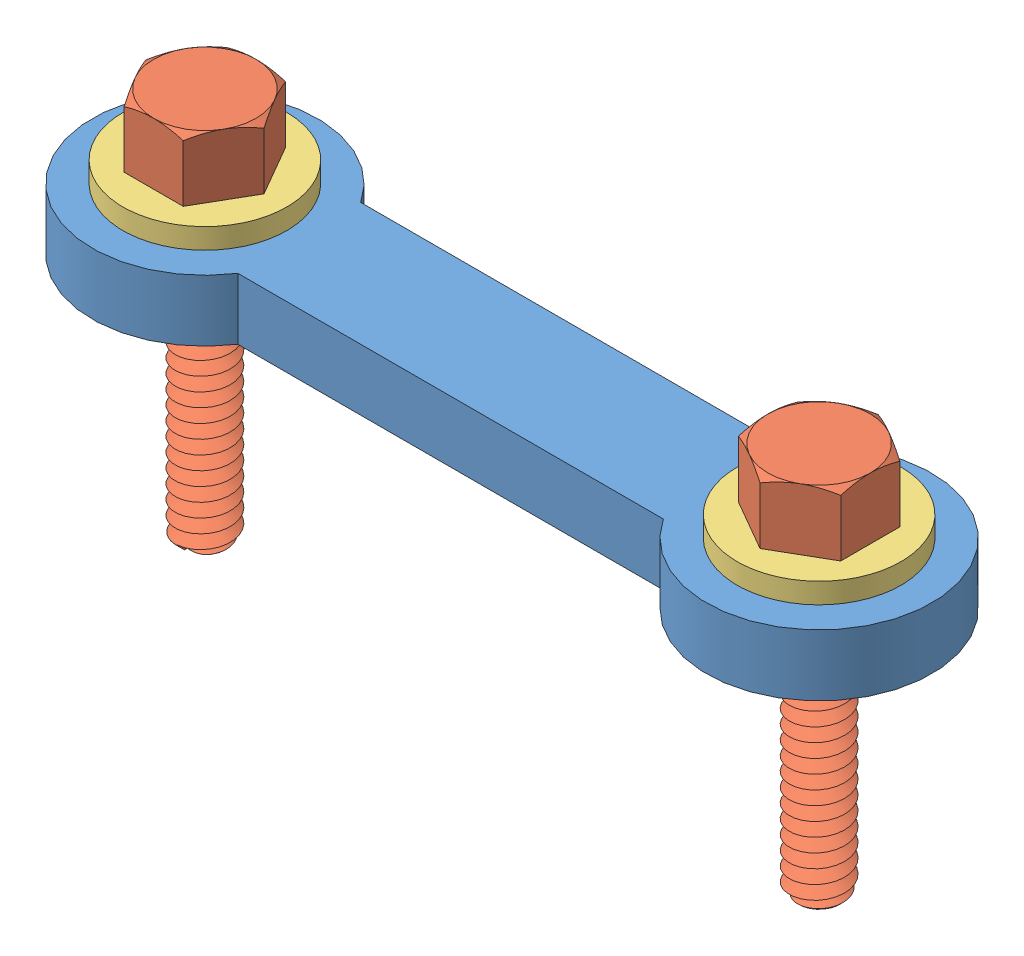
SolidWorks assembly Assem7_3, configuration Default. Lengths in mm.
Overall size (41 19.28 11).
6 component instances, 3 part files, 15 mates.
Components (placement in the parent):
- Part10-1: Part10 [Default] at origin size (41 3 11)
- straf3_dolg16_2-1: straf3_dolg16_2 [Default] at (0 4 0) x (0 1 0) z (0 0 1) size (19.28 5.77 5)
- sajbna6-1: sajbna6 [Default] at (0 3 0) size (8 1 8)
- sajbna6-2: sajbna6 [Default] at (30 3 0) size (8 1 8)
- sajbna6-3: sajbna6 [Default] at (30 -1 0) size (8 1 8)
- straf3_dolg16_2-2: straf3_dolg16_2 [Default] at (30 4 0) x (0 1 0) z (-1 0 0) size (19.28 5.77 5)
Mates (geometry in assembly coordinates):
- Concentric1: concentric anti-aligned: cylinder of Part10-1 through (0 3 0) axis (0 -1 0) radius 1.5; cylinder of straf3_dolg16_2-1 through (0 -12 0) axis (0 1 0) radius 1.5
- Concentric2: concentric aligned: cylinder of Part10-1 through (0 3 0) axis (0 -1 0) radius 1.5; cylinder of sajbna6-1 through (0 4 0) axis (0 -1 0) radius 1.5
- Coincident1: coincident anti-aligned: plane of straf3_dolg16_2-1 through (0 4 0) normal (0 -1 0); plane of sajbna6-1 through (0 4 0) normal (0 1 0)
- Coincident2: coincident anti-aligned: plane of Part10-1 through (0 3 0) normal (0 1 0); plane of sajbna6-1 through (0 3 0) normal (0 -1 0)
- Concentric3: concentric aligned: cylinder of Part10-1 through (30 3 0) axis (0 -1 0) radius 1.5; cylinder of sajbna6-2 through (30 4 0) axis (0 -1 0) radius 1.5
- Coincident3: coincident anti-aligned: plane of Part10-1 through (0 3 0) normal (0 1 0); plane of sajbna6-2 through (30 3 0) normal (0 -1 0)
- Coincident4: coincident anti-aligned: plane of Part10-1 through (0 0 0) normal (0 -1 0); plane of sajbna6-3 through (30 0 0) normal (0 1 0)
- Concentric4: concentric aligned: cylinder of Part10-1 through (30 3 0) axis (0 -1 0) radius 1.5; cylinder of sajbna6-3 through (30 0 0) axis (0 -1 0) radius 1.5
- Concentric5: concentric anti-aligned: cylinder of Part10-1 through (30 3 0) axis (0 -1 0) radius 1.5; cylinder of straf3_dolg16_2-2 through (30 -12 0) axis (0 1 0) radius 1.5
- Coincident5: coincident anti-aligned: plane of sajbna6-2 through (30 4 0) normal (0 1 0); plane of straf3_dolg16_2-2 through (30 4 0) normal (0 -1 0)
- Parallel1: parallel aligned: plane of straf3_dolg16_2-1 through (-1.4434 7 2.5) normal (0 0 1); plane of assembly
- Parallel2: parallel aligned: plane of sajbna6-1 through (0 3 0) normal (0 0 1); plane of assembly
- Parallel3: parallel aligned: plane of sajbna6-2 through (30 3 0) normal (0 0 1); plane of assembly
- Parallel4: parallel aligned: plane of sajbna6-3 through (30 -1 0) normal (0 0 1); plane of assembly
- Parallel5: parallel anti-aligned: plane of straf3_dolg16_2-2; plane of assembly
